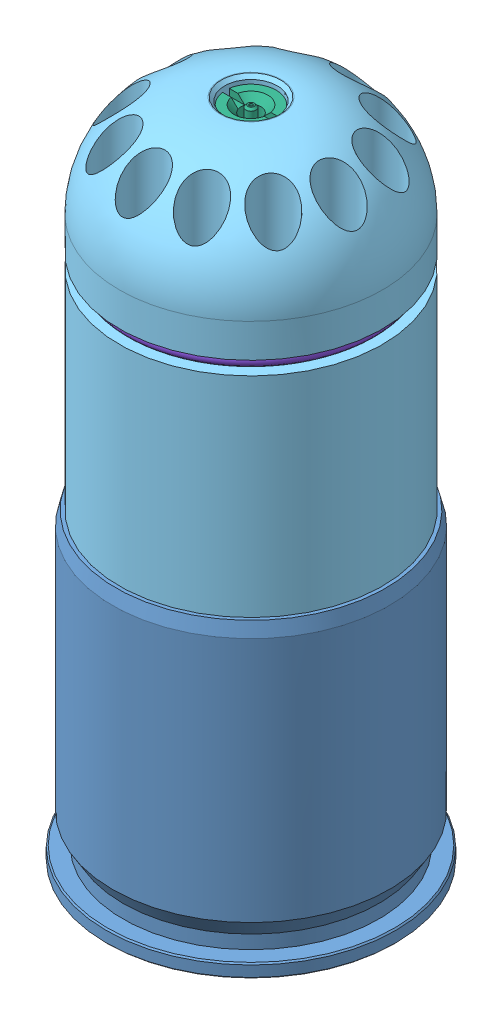
SolidWorks assembly 40mm-Klein, configuration Standard. Lengths in mm.
Overall size (51.21 98 51.21).
11 component instances, 8 part files, 20 mates.
Components (placement in the parent):
- Boden-G-1: Boden-G [Standard] at (-10.8436 -22.8172 45) size (42.9 45 42.9)
- Drücker-G-1: Drücker-G [Standard] at (-10.8436 -22.8172 45) size (14 23 14)
- value-1: value [Standard] at (-10.8436 -4.0172 45) size (20 21.5 20)
- Lock-Kugel-1: Lock-Kugel [Standard] at (-10.8436 -3.0172 55) size (4 4 4)
- Lock-Kugel-2: Lock-Kugel [Standard] at (-0.8436 -3.0172 45) size (4 4 4)
- Lock-Kugel-3: Lock-Kugel [Standard] at (-20.8436 -3.0172 45) size (4 4 4)
- Lock-Kugel-4: Lock-Kugel [Standard] at (-10.8436 -3.0172 35) size (4 4 4)
- Vorn-K-1: Vorn-K [Standard] at (-10.8436 5.6828 45) x (0.99501 0 0.099776) z (-0.099776 0 0.99501) size (39 69.5 39)
- Einfüllventil-1: Einfüllventil [Standard] at (-10.8436 61.6828 45) size (7.5 12.5 7.5)
- value-gegen-1: value-gegen [Standard] at (-10.8436 11.4828 45) x (1 0 -0.000025) z (0.000025 0 1) size (17.5 18.5 17.5)
- O-Ring oben-1: O-Ring oben [Standard] at (-10.8436 54.1828 45) x (-0.837169 0 -0.546944) z (-0.546944 0 0.837169) size (37 2 37)
Mates (geometry in assembly coordinates):
- Konzentrisch1: concentric anti-aligned: cylinder of Boden-G-1 through (-10.8436 -21.8172 45) axis (0 1 0) radius 7; cylinder of Drücker-G-1 through (-10.8436 -12.8172 45) axis (0 -1 0) radius 7
- Deckungsgleich1: coincident aligned: plane of Boden-G-1 through (-10.8436 -22.8172 45) normal (0 -1 0); plane of Drücker-G-1 through (-10.8436 -22.8172 45) normal (0 -1 0)
- Konzentrisch2: concentric: cylinder of value-1 through (-10.8436 49.628 35) axis (0 0 1) radius 2; sphere of Lock-Kugel-1
- Tangential2: tangent: curve of value-1; sphere of Lock-Kugel-1
- Konzentrisch3: concentric: cylinder of value-1 through (-20.8436 49.628 45) axis (1 0 0) radius 2; sphere of Lock-Kugel-2
- Tangential4: tangent: curve of value-1; sphere of Lock-Kugel-2
- Konzentrisch4: concentric: cylinder of value-1 through (-10.8436 49.628 35) axis (0 0 1) radius 2; sphere of Lock-Kugel-4
- Tangential6: tangent: curve of value-1; sphere of Lock-Kugel-4
- Konzentrisch5: concentric: cylinder of value-1 through (-20.8436 49.628 45) axis (1 0 0) radius 2; sphere of Lock-Kugel-3
- Tangential8: tangent: curve of value-1; sphere of Lock-Kugel-3
- Deckungsgleich2: coincident aligned: circle of Boden-G-1; cylinder of value-1 through (-10.8436 55.628 45) axis (0 -1 0) radius 10
- Konzentrisch6: concentric anti-aligned: cylinder of Vorn-K-1 through (-10.8436 56.328 45) axis (0 1 0) radius 2; cylinder of Einfüllventil-1 through (-10.8436 122.828 45) axis (0 -1 0) radius 2
- Deckungsgleich3: coincident anti-aligned: plane of Vorn-K-1 through (-10.8436 122.828 45) normal (0 1 0); plane of Einfüllventil-1 through (-10.8436 122.828 45) normal (0 -1 0)
- Deckungsgleich4: coincident anti-aligned: plane of Vorn-K-1 through (-10.8436 64.128 45) normal (0 -1 0); plane of value-gegen-1 through (-10.8436 64.128 45) normal (0 1 0)
- Konzentrisch7: concentric aligned: cylinder of Vorn-K-1 through (-10.8436 113.328 45) axis (0 -1 0) radius 7.5; cylinder of value-gegen-1 through (-10.8436 80.628 45) axis (0 -1 0) radius 7.5
- Deckungsgleich5: coincident anti-aligned: plane of value-1 through (-10.8436 62.128 45) normal (0 1 0); plane of value-gegen-1 through (-10.8436 62.128 45) normal (0 -1 0)
- Konzentrisch8: concentric aligned: cylinder of value-1 through (-10.8436 68.128 45) axis (0 -1 0) radius 4.95; cylinder of value-gegen-1 through (-10.8436 69.928 45) axis (0 -1 0) radius 5
- Deckungsgleich6: coincident anti-aligned: plane of Boden-G-1 through (-10.8436 22.1828 45) normal (0 1 0); plane of Vorn-K-1 through (-10.8436 22.1828 45) normal (0 -1 0)
- Tangential9: tangent: plane of Vorn-K-1 through (-32.7123 53.1828 42.8071) normal (0 1 0); torus of O-Ring oben-1
- Tangential10: tangent: cylinder of Vorn-K-1 through (-10.8436 75.1828 45) axis (0 1 0) radius 16.5; torus of O-Ring oben-1
